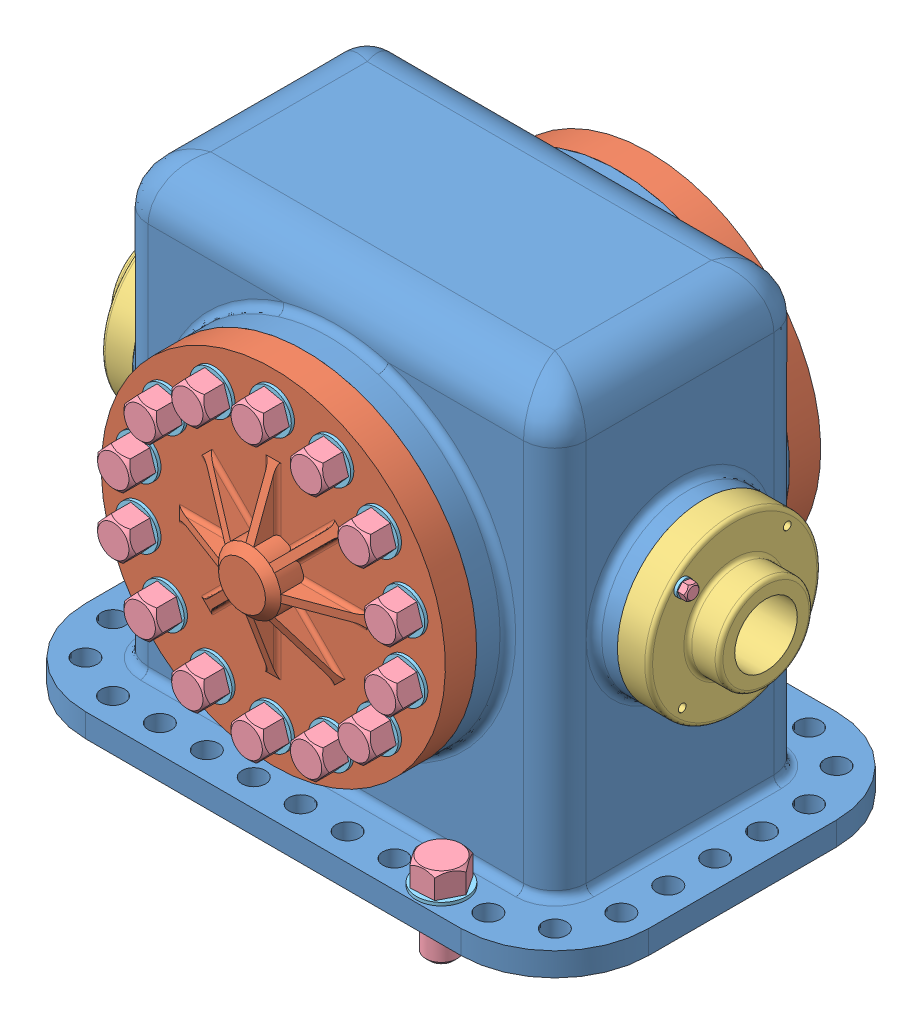
SolidWorks assembly Assem1, configuration Default. Lengths in mm.
Overall size (247.65 201.93 177.8).
56 component instances, 5 part files, 18 mates.
Components (placement in the parent):
- Housing-1: Housing [Default] at origin size (228.6 187.33 152.4)
- Front_Plate-2: Front_Plate [Default] at (0 0 63.5) x (-1 0 0) z (0 1 0) size (139.7 25.4 139.7)
- Front_Plate-5: Front_Plate [Default] at (0 0 -63.5) x (-1 0 0) z (0 -1 0) size (139.7 25.4 139.7)
- Side_Plate-1: Side_Plate [Default] at (98.425 0 0) x (0 -1 0) z (0 0 1) size (69.85 25.4 69.85)
- Side_Plate-3: Side_Plate [Default] at (-98.425 0 0) x (0 -1 0) z (0 0 -1) size (69.85 25.4 69.85)
- Bolt_Assembly-1: Bolt_Assembly [0.5 in HRD] at (57.15 -113.03 65.0875) x (-0.056108 0 -0.998425) z (0.998425 0 -0.056108) size (20.32 34.92 20.32)
  - Bolt-1: Bolt [.5 bolt] at origin size (16.5 34.92 19.05)
  - Washer-1: Washer [.5 washer] at (0 24.13 0) size (20.32 1.27 20.32)
- Bolt_Assembly-2: Bolt_Assembly [0.375 in HRD] at (54.1694 12.3638 52.07) x (0.741312 -0.67116 0) z (-0.67116 -0.741312 0) size (17.14 34.92 17.14)
  - Bolt-1: Bolt [.375 bolt] at origin size (13.75 34.92 15.88)
  - Washer-1: Washer [.375 washer] at (0 24.13 0) size (17.14 1.27 17.14)
- Bolt_Assembly-3: Bolt_Assembly [0.125 in HRD] at (83.82 21.3281 21.3281) x (0 -0.381849 0.924225) z (0 0.924225 0.381849) size (6.73 31.75 6.98)
  - Bolt-1: Bolt [.125 bolt] at origin size (5.5 31.75 6.98)
  - Washer-1: Washer [.125 washer] at (0 27.305 0) size (6.73 1.27 6.73)
- Bolt_Assembly-19: Bolt_Assembly [0.375 in HRD] at (54.1694 -12.3638 52.07) x (0.741312 -0.67116 0) z (-0.67116 -0.741312 0) size (17.14 34.92 17.14)
  - Bolt-1: Bolt [.375 bolt] at origin size (13.75 34.92 15.88)
  - Washer-1: Washer [.375 washer] at (0 24.13 0) size (17.14 1.27 17.14)
- Bolt_Assembly-20: Bolt_Assembly [0.375 in HRD] at (43.4405 -34.6427 52.07) x (0.741312 -0.67116 0) z (-0.67116 -0.741312 0) size (17.14 34.92 17.14)
  - Bolt-1: Bolt [.375 bolt] at origin size (13.75 34.92 15.88)
  - Washer-1: Washer [.375 washer] at (0 24.13 0) size (17.14 1.27 17.14)
- Bolt_Assembly-21: Bolt_Assembly [0.375 in HRD] at (24.1077 -50.0601 52.07) x (0.741312 -0.67116 0) z (-0.67116 -0.741312 0) size (17.14 34.92 17.14)
  - Bolt-1: Bolt [.375 bolt] at origin size (13.75 34.92 15.88)
  - Washer-1: Washer [.375 washer] at (0 24.13 0) size (17.14 1.27 17.14)
- Bolt_Assembly-22: Bolt_Assembly [0.375 in HRD] at (0 -55.5625 52.07) x (0.741312 -0.67116 0) z (-0.67116 -0.741312 0) size (17.14 34.92 17.14)
  - Bolt-1: Bolt [.375 bolt] at origin size (13.75 34.92 15.88)
  - Washer-1: Washer [.375 washer] at (0 24.13 0) size (17.14 1.27 17.14)
- Bolt_Assembly-23: Bolt_Assembly [0.375 in HRD] at (-24.1077 -50.0601 52.07) x (0.741312 -0.67116 0) z (-0.67116 -0.741312 0) size (17.14 34.92 17.14)
  - Bolt-1: Bolt [.375 bolt] at origin size (13.75 34.92 15.88)
  - Washer-1: Washer [.375 washer] at (0 24.13 0) size (17.14 1.27 17.14)
- Bolt_Assembly-24: Bolt_Assembly [0.375 in HRD] at (-43.4405 -34.6427 52.07) x (0.741312 -0.67116 0) z (-0.67116 -0.741312 0) size (17.14 34.92 17.14)
  - Bolt-1: Bolt [.375 bolt] at origin size (13.75 34.92 15.88)
  - Washer-1: Washer [.375 washer] at (0 24.13 0) size (17.14 1.27 17.14)
- Bolt_Assembly-25: Bolt_Assembly [0.375 in HRD] at (-54.1694 -12.3638 52.07) x (0.741312 -0.67116 0) z (-0.67116 -0.741312 0) size (17.14 34.92 17.14)
  - Bolt-1: Bolt [.375 bolt] at origin size (13.75 34.92 15.88)
  - Washer-1: Washer [.375 washer] at (0 24.13 0) size (17.14 1.27 17.14)
- Bolt_Assembly-26: Bolt_Assembly [0.375 in HRD] at (-54.1694 12.3638 52.07) x (0.741312 -0.67116 0) z (-0.67116 -0.741312 0) size (17.14 34.92 17.14)
  - Bolt-1: Bolt [.375 bolt] at origin size (13.75 34.92 15.88)
  - Washer-1: Washer [.375 washer] at (0 24.13 0) size (17.14 1.27 17.14)
- Bolt_Assembly-27: Bolt_Assembly [0.375 in HRD] at (-43.4405 34.6427 52.07) x (0.741312 -0.67116 0) z (-0.67116 -0.741312 0) size (17.14 34.92 17.14)
  - Bolt-1: Bolt [.375 bolt] at origin size (13.75 34.92 15.88)
  - Washer-1: Washer [.375 washer] at (0 24.13 0) size (17.14 1.27 17.14)
- Bolt_Assembly-28: Bolt_Assembly [0.375 in HRD] at (-24.1077 50.0601 52.07) x (0.741312 -0.67116 0) z (-0.67116 -0.741312 0) size (17.14 34.92 17.14)
  - Bolt-1: Bolt [.375 bolt] at origin size (13.75 34.92 15.88)
  - Washer-1: Washer [.375 washer] at (0 24.13 0) size (17.14 1.27 17.14)
- Bolt_Assembly-29: Bolt_Assembly [0.375 in HRD] at (0 55.5625 52.07) x (0.741312 -0.67116 0) z (-0.67116 -0.741312 0) size (17.14 34.92 17.14)
  - Bolt-1: Bolt [.375 bolt] at origin size (13.75 34.92 15.88)
  - Washer-1: Washer [.375 washer] at (0 24.13 0) size (17.14 1.27 17.14)
- Bolt_Assembly-30: Bolt_Assembly [0.375 in HRD] at (24.1077 50.0601 52.07) x (0.741312 -0.67116 0) z (-0.67116 -0.741312 0) size (17.14 34.92 17.14)
  - Bolt-1: Bolt [.375 bolt] at origin size (13.75 34.92 15.88)
  - Washer-1: Washer [.375 washer] at (0 24.13 0) size (17.14 1.27 17.14)
- Bolt_Assembly-31: Bolt_Assembly [0.375 in HRD] at (43.4405 34.6427 52.07) x (0.741312 -0.67116 0) z (-0.67116 -0.741312 0) size (17.14 34.92 17.14)
  - Bolt-1: Bolt [.375 bolt] at origin size (13.75 34.92 15.88)
  - Washer-1: Washer [.375 washer] at (0 24.13 0) size (17.14 1.27 17.14)
- Bolt_Assembly-32: Bolt_Assembly [0.375 in HRD] at (0 0 52.07) x (0.741312 -0.67116 0) z (-0.67116 -0.741312 0) size (17.14 34.92 17.14)
  - Bolt-1: Bolt [.375 bolt] at origin size (13.75 34.92 15.88)
  - Washer-1: Washer [.375 washer] at (0 24.13 0) size (17.14 1.27 17.14)
Mates (geometry in assembly coordinates):
- Coincident21: coincident anti-aligned: plane of Housing-1 through (0 69.85 63.5) normal (0 0 1); plane of Front_Plate-2 through (-69.85 0 63.5) normal (0 0 -1)
- Coincident31: coincident anti-aligned: plane of Housing-1 through (0 0 0) normal (1 0 0); plane of Front_Plate-2 through (0 0 63.5) normal (-1 0 0)
- Coincident41: coincident aligned: plane of Housing-1 through (0 0 0) normal (0 1 0); plane of Front_Plate-2 through (0 0 63.5) normal (0 1 0)
- Coincident111: coincident anti-aligned: plane of Housing-1 through (0 69.85 -63.5) normal (0 0 -1); plane of Front_Plate-5 through (-69.85 0 -63.5) normal (0 0 1)
- Coincident121: coincident anti-aligned: plane of Housing-1 through (0 0 0) normal (1 0 0); plane of Front_Plate-5 through (0 0 -63.5) normal (-1 0 0)
- Coincident131: coincident anti-aligned: plane of Housing-1 through (0 0 0) normal (0 1 0); plane of Front_Plate-5 through (0 0 -63.5) normal (0 -1 0)
- Coincident141: coincident anti-aligned: plane of Housing-1 through (98.425 34.925 0) normal (1 0 0); plane of Side_Plate-1 through (98.425 -34.925 0) normal (-1 0 0)
- Coincident151: coincident aligned: plane of Housing-1 through (0 0 0) normal (0 0 1); plane of Side_Plate-1 through (98.425 0 0) normal (0 0 1)
- Coincident161: coincident anti-aligned: plane of Housing-1 through (0 0 0) normal (0 1 0); plane of Side_Plate-1 through (98.425 0 0) normal (0 -1 0)
- Coincident171: coincident anti-aligned: plane of Housing-1 through (-98.425 34.925 0) normal (-1 0 0); plane of Side_Plate-3 through (-98.425 -34.925 0) normal (1 0 0)
- Coincident181: coincident anti-aligned: plane of Housing-1 through (0 0 0) normal (0 0 1); plane of Side_Plate-3 through (-98.425 0 0) normal (0 0 -1)
- Coincident191: coincident anti-aligned: plane of Housing-1 through (0 0 0) normal (0 1 0); plane of Side_Plate-3 through (-98.425 0 0) normal (0 -1 0)
- Concentric11: concentric anti-aligned: cylinder of Housing-1 through (57.15 -98.425 65.0875) axis (0 1 0) radius 4.7625; cylinder of Bolt_Assembly-1/Washer-1 through (57.15 -87.63 65.0875) axis (0 -1 0) radius 6.35
- Coincident1921: coincident anti-aligned: plane of Housing-1 through (-76.2 -88.9 38.1) normal (0 1 0); plane of Bolt_Assembly-1/Washer-1 through (57.15 -88.9 65.0875) normal (0 -1 0)
- Concentric21: concentric anti-aligned: cylinder of Front_Plate-2 through (54.1694 12.3638 63.5) axis (0 0 1) radius 6.35; cylinder of Bolt_Assembly-2/Washer-1 through (54.1694 12.3638 77.47) axis (0 0 -1) radius 4.7625
- Coincident1931: coincident anti-aligned: plane of Front_Plate-2 through (-12.7 0 76.2) normal (0 0 1); plane of Bolt_Assembly-2/Washer-1 through (54.1694 12.3638 76.2) normal (0 0 -1)
- Concentric31: concentric anti-aligned: cylinder of Side_Plate-1 through (98.425 21.3281 21.3281) axis (1 0 0) radius 1.5875; cylinder of Bolt_Assembly-3/Washer-1 through (112.395 21.3281 21.3281) axis (-1 0 0) radius 1.5875
- Coincident1941: coincident anti-aligned: plane of Side_Plate-1 through (111.125 -20.6375 0) normal (1 0 0); plane of Bolt_Assembly-3/Washer-1 through (111.125 21.3281 21.3281) normal (-1 0 0)
